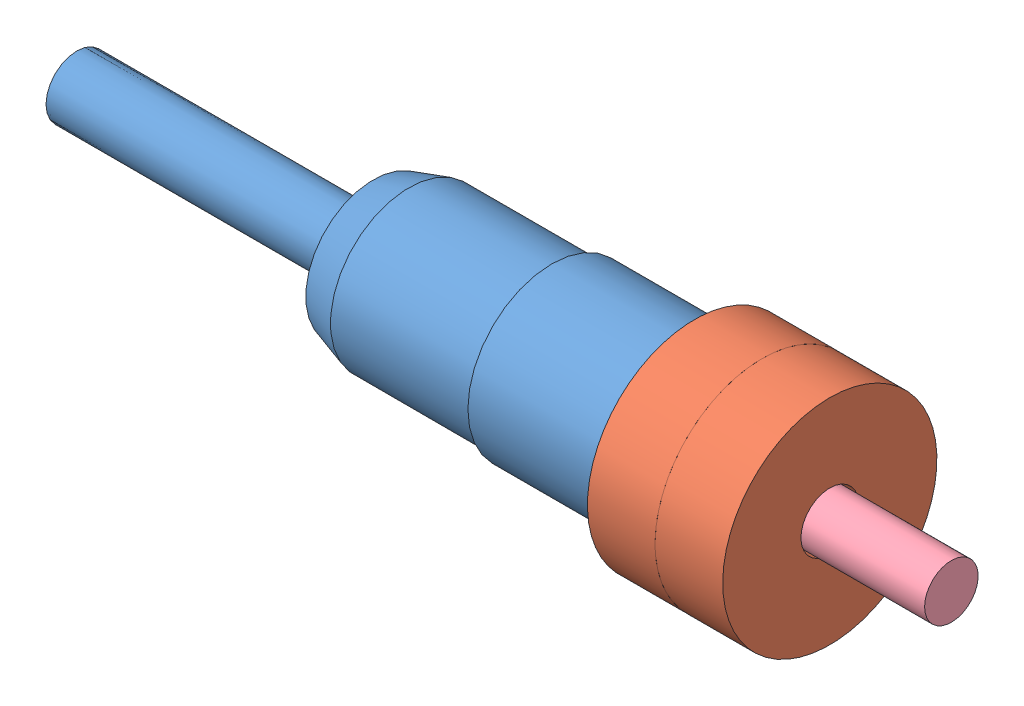
SolidWorks assembly bed calibration device, configuration Default. Lengths in mm.
Overall size (49 12.48 12.48).
6 component instances, 4 part files, 8 mates.
Components (placement in the parent):
- metal knurl-1: metal knurl [Default] at (-2.1532 2.6055 -5.8442) size (34.61 9.4 9.4)
- Magnet (12x3.79mm)-1: Magnet (12x3.79mm) [Default] at (313.6925 56.1204 -10.3541) x (0 0.023613 0.999721) z (-1 0 0) size (12 12 3.79)
- countersunk flat head cross recess screw_iso-1: countersunk flat head cross recess screw_iso [ISO 7046-1 - M3 x 6 - Z --- 6N] at (313.1507 79.3124 -5.8442) x (-1 0 0) z (0 0.092314 -0.99573) size (6 5.5 5.5)
- countersunk flat head cross recess screw_iso-2: countersunk flat head cross recess screw_iso [ISO 7046-1 - M3 x 10 - Z --- 10N] at (314.2925 79.3124 -5.8442) x (1 0 0) z (0 0.392827 0.919612) size (10 5.5 5.5)
- Magnet (12x3.79mm)-2: Magnet (12x3.79mm) [Default] at (313.6925 102.5788 -9.9525) x (0 -0.040894 0.999163) z (1 0 0) size (12 12 3.79)
- sleve-1: sleve [Default] at (310.0825 118.8102 344.5108) x (0 0.943746 -0.330671) z (1 0 0) (suppressed, hidden)
Mates (geometry in assembly coordinates):
- Coincident787258: coincident: plane of Magnet (12x3.79mm)-1 through (309.9025 79.3124 -5.8442) normal (-1 0 0); plane of metal knurl-1 through (309.9025 2.6055 -5.8442) normal (1 0 0)
- Coincident786953: coincident: cone of Magnet (12x3.79mm)-1 through (313.6925 79.3124 -5.8442) axis (-1 0 0); cone of countersunk flat head cross recess screw_iso-1 through (312.7507 79.3124 -5.8442) axis (-1 0 0)
- Concentric401189: concentric: cylinder of assembly; cylinder of Magnet (12x3.79mm)-2 through (317.4825 79.3124 -5.8442) axis (-1 0 0) radius 6; cylinder of sleve-1 through (317.4825 79.3124 -5.8442) axis (-1 0 0) radius 5.992
- Coincident78718798: coincident: plane of assembly; plane of sleve-1 through (317.4825 79.3124 -5.8442) normal (-1 0 0); plane of Magnet (12x3.79mm)-2 through (317.4825 79.3124 -5.8442) normal (1 0 0)
- Concentric4005713: concentric: cylinder of assembly; cylinder of Magnet (12x3.79mm)-1 through (309.9025 79.3124 -5.8442) axis (1 0 0) radius 6; cylinder of sleve-1 through (317.4825 79.3124 -5.8442) axis (-1 0 0) radius 8.492
- Coincident78718800: coincident: cone of Magnet (12x3.79mm)-2 through (313.6925 79.3124 -5.8442) axis (1 0 0); cone of countersunk flat head cross recess screw_iso-2 through (314.6925 79.3124 -5.8442) axis (1 0 0)
- Concentric4005715: concentric: cylinder of assembly; cylinder of metal knurl-1 through (275.2938 79.3124 -5.8442) axis (-1 0 0) radius 4.7; cylinder of sleve-1 through (317.4825 79.3124 -5.8442) axis (-1 0 0) radius 5.992
- Coincident78718801: coincident: plane of Magnet (12x3.79mm)-1 through (313.6925 79.3124 -5.8442) normal (1 0 0); plane of Magnet (12x3.79mm)-2 through (313.6925 79.3124 -5.8442) normal (-1 0 0)
